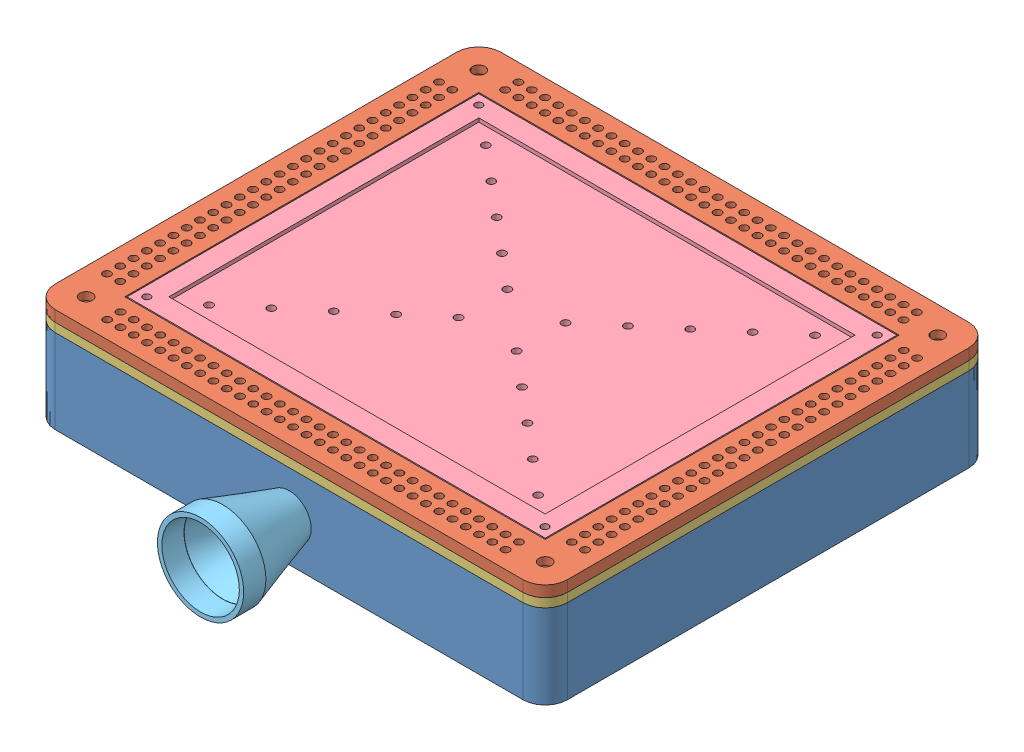
SolidWorks assembly Assembly_TK_simplified, configuration Default. Lengths in mm.
Overall size (231.4 50.4 241.4).
5 component instances, 5 part files, 14 mates.
Components (placement in the parent):
- Container_TK-1: Container_TK [Default] at origin size (231.4 38 201.4)
- Lifter_TK-1: Lifter_TK [Default] at (0 42 0) size (231.4 7.5 201.4)
- Lid_TK_simplified-1: Lid_TK_simplified [Default] at (0 38 0) size (231.4 9 201.4)
- PCB_holder_TK_simplified-2: PCB_holder_TK_simplified [Default] at (0 42 0) size (188.9 5 158.9)
- 35mm_NozzleAdapter-1: 35mm_NozzleAdapter [Default] at (0 19 130.7) x (0.986793 -0.161984 0) z (0.161984 0.986793 0) size (39 50 39)
Mates (geometry in assembly coordinates):
- Coincident1: coincident aligned: plane of Container_TK-1 through (0 0 0) normal (0 0 1)
- Coincident3: coincident aligned: plane of Container_TK-1 through (0 0 0) normal (0 1 0)
- Coincident4: coincident aligned: plane of Container_TK-1 through (0 0 0) normal (1 0 0)
- Coincident5: coincident aligned: plane of Lid_TK_simplified-1 through (0 38 0) normal (0 0 1)
- Coincident6: coincident aligned: plane of Lid_TK_simplified-1 through (0 38 0) normal (1 0 0)
- Coincident7: coincident anti-aligned: plane of Container_TK-1 through (0 38 0) normal (0 1 0); plane of Lid_TK_simplified-1 through (0 38 0) normal (0 -1 0)
- Coincident8: coincident aligned: plane of Lifter_TK-1 through (0 42 0) normal (0 0 1)
- Coincident9: coincident aligned: plane of Lifter_TK-1 through (0 42 0) normal (1 0 0)
- Coincident12: coincident anti-aligned: plane of Lifter_TK-1 through (0 42 0) normal (0 -1 0); plane of Lid_TK_simplified-1 through (0 42 0) normal (0 1 0)
- Coincident15: coincident aligned: plane of PCB_holder_TK_simplified-2 through (0 42 0) normal (0 0 1)
- Coincident16: coincident aligned: plane of PCB_holder_TK_simplified-2 through (0 42 0) normal (1 0 0)
- Coincident17: coincident anti-aligned: plane of Lid_TK_simplified-1 through (0 42 0) normal (0 1 0); plane of PCB_holder_TK_simplified-2 through (0 42 0) normal (0 -1 0)
- Concentric2: concentric aligned: cylinder of Container_TK-1 through (0 19 98.7) axis (0 0 1) radius 10; cylinder of 35mm_NozzleAdapter-1 through (0 19 90.7) axis (0 0 1) radius 10
- Coincident18: coincident anti-aligned: plane of Container_TK-1 through (-115.7 38 100.7) normal (0 0 1); circle of 35mm_NozzleAdapter-1
